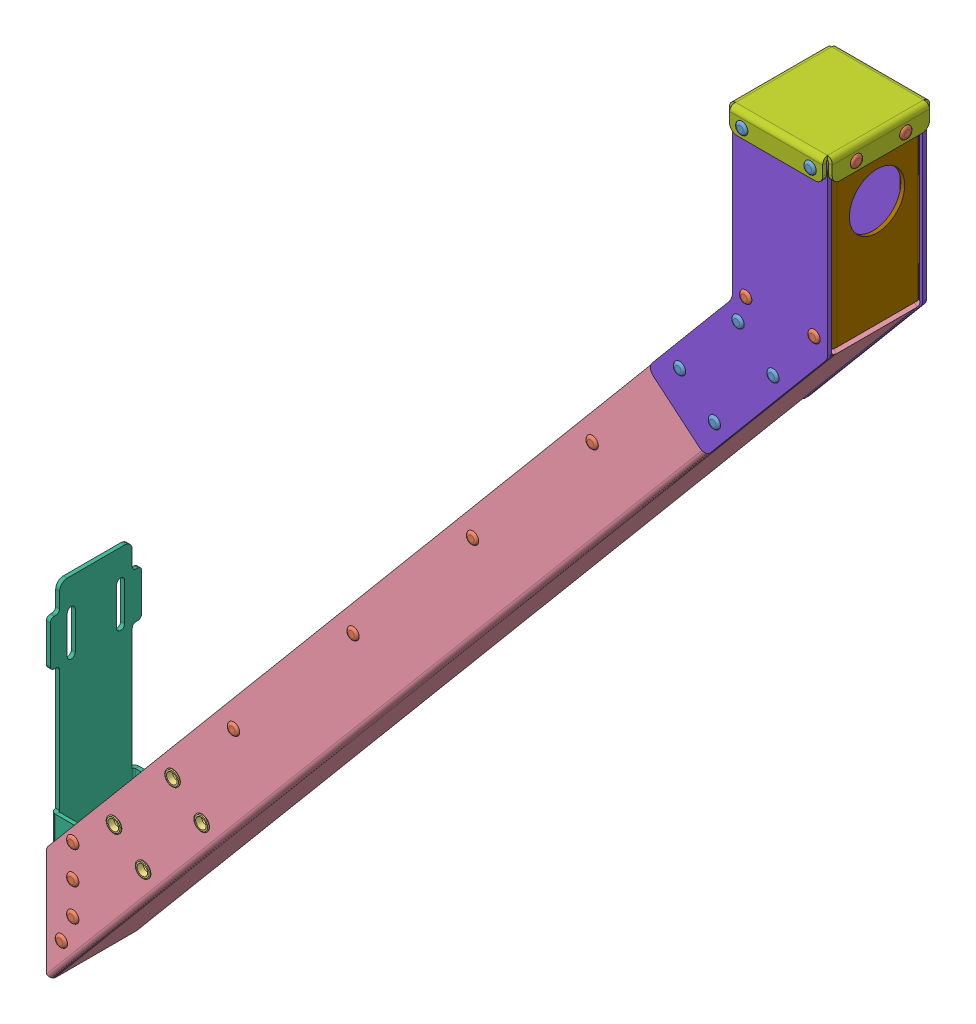
SolidWorks assembly GE-20011, configuration Default. Lengths in mm.
Overall size (724.49 954.81 92.63).
53 component instances, 9 part files, 51 mates.
Components (placement in the parent):
- rivet_.1875_.376-.5-1: rivet_.1875_.376-.5 [Default] at (581.956 765.2734 3.2639) x (-0.945935 -0.324357 0) z (0 0 1) size (10.01 10.01 19.38)
- rivet_.1875_.376-.5-2: rivet_.1875_.376-.5 [Default] at (581.956 765.2734 -79.6417) x (0.53005 0.847966 0) z (0 0 -1) size (10.01 10.01 19.38)
- rivet_.1875_.251-.375-49: rivet_.1875_.251-.375 [Default] at (456.6394 613.4571 0) x (-0.588171 -0.808736 0) z (0 0 1) size (10.01 10.01 16.21)
- rivet_.1875_.251-.375-50: rivet_.1875_.251-.375 [Default] at (456.6394 613.4571 -76.3778) x (0.853096 -0.521754 0) z (0 0 -1) size (10.01 10.01 16.21)
- rivet_.1875_.251-.375-51: rivet_.1875_.251-.375 [Default] at (12.7 30.489 -76.3778) x (0.853096 -0.521754 0) z (0 0 -1) size (10.01 10.01 16.21)
- rivet_.1875_.251-.375-52: rivet_.1875_.251-.375 [Default] at (12.7 30.489 0) x (-0.588171 -0.808736 0) z (0 0 1) size (10.01 10.01 16.21)
- rivnut_.25_20_.165-.260-1: rivnut_.25_20_.165-.260 [Installed] at (105.7322 195.0203 0.762) x (-0.98091 0.19446 0) z (0.19446 0.98091 0) size (12.7 15.11 12.7)
- rivnut_.25_20_.165-.260-9: rivnut_.25_20_.165-.260 [Installed] at (105.7322 195.0203 -77.1398) x (0.831607 0.555365 0) z (-0.555365 0.831607 0) size (12.7 15.11 12.7)
- GE-20011 - 01-1: GE-20011 - 01 [Default] at origin size (656.55 781.22 76.38)
- GE-20011 - 02-1: GE-20011 - 02 [Default] at (576.309 778.3012 -38.1889) x (0 0 -1) z (0.642788 0.766044 0) size (69.85 57.15 838.2)
- rivnut_.25_20_.165-.260-10: rivnut_.25_20_.165-.260 [Installed] at (56.7517 136.6477 -77.1398) x (0.831607 0.555365 0) z (-0.555365 0.831607 0) size (12.7 15.11 12.7)
- rivnut_.25_20_.165-.260-11: rivnut_.25_20_.165-.260 [Installed] at (130.0541 174.6118 -77.1398) x (0.831607 0.555365 0) z (-0.555365 0.831607 0) size (12.7 15.11 12.7)
- rivnut_.25_20_.165-.260-12: rivnut_.25_20_.165-.260 [Installed] at (81.0737 116.2392 -77.1398) x (0.831607 0.555365 0) z (-0.555365 0.831607 0) size (12.7 15.11 12.7)
- rivnut_.25_20_.165-.260-6: rivnut_.25_20_.165-.260 [Installed] at (56.7517 136.6477 0.762) x (-0.98091 0.19446 0) z (0.19446 0.98091 0) size (12.7 15.11 12.7)
- rivnut_.25_20_.165-.260-7: rivnut_.25_20_.165-.260 [Installed] at (130.0541 174.6118 0.762) x (-0.98091 0.19446 0) z (0.19446 0.98091 0) size (12.7 15.11 12.7)
- rivnut_.25_20_.165-.260-8: rivnut_.25_20_.165-.260 [Installed] at (81.0737 116.2392 0.762) x (-0.98091 0.19446 0) z (0.19446 0.98091 0) size (12.7 15.11 12.7)
- GE-20011 - 06-1: GE-20011 - 06 [Default] at (0 1.914 -38.1889) x (0 0 1) z (-1 0 0) size (76.38 279.4 38.1)
- rivet_.1875_.251-.375-53: rivet_.1875_.251-.375 [Default] at (22.225 106.689 -76.3778) x (0.853096 -0.521754 0) z (0 0 -1) size (10.01 10.01 16.21)
- rivet_.1875_.251-.375-54: rivet_.1875_.251-.375 [Default] at (22.225 79.7015 -76.3778) x (0.853096 -0.521754 0) z (0 0 -1) size (10.01 10.01 16.21)
- rivet_.1875_.251-.375-55: rivet_.1875_.251-.375 [Default] at (22.225 52.714 -76.3778) x (0.853096 -0.521754 0) z (0 0 -1) size (10.01 10.01 16.21)
- rivet_.1875_.251-.375-56: rivet_.1875_.251-.375 [Default] at (22.225 106.689 0) x (-0.588171 -0.808736 0) z (0 0 1) size (10.01 10.01 16.21)
- rivet_.1875_.251-.375-57: rivet_.1875_.251-.375 [Default] at (22.225 79.7015 0) x (-0.588171 -0.808736 0) z (0 0 1) size (10.01 10.01 16.21)
- rivet_.1875_.251-.375-58: rivet_.1875_.251-.375 [Default] at (22.225 52.714 0) x (-0.588171 -0.808736 0) z (0 0 1) size (10.01 10.01 16.21)
- rivet_.1875_.251-.375-59: rivet_.1875_.251-.375 [Default] at (356.6377 494.2797 0) x (-0.588171 -0.808736 0) z (0 0 1) size (10.01 10.01 16.21)
- rivet_.1875_.251-.375-60: rivet_.1875_.251-.375 [Default] at (256.636 375.1024 0) x (-0.588171 -0.808736 0) z (0 0 1) size (10.01 10.01 16.21)
- rivet_.1875_.251-.375-61: rivet_.1875_.251-.375 [Default] at (156.6343 255.925 0) x (-0.588171 -0.808736 0) z (0 0 1) size (10.01 10.01 16.21)
- rivet_.1875_.251-.375-63: rivet_.1875_.251-.375 [Default] at (356.6377 494.2797 -76.3778) x (0.853096 -0.521754 0) z (0 0 -1) size (10.01 10.01 16.21)
- rivet_.1875_.251-.375-64: rivet_.1875_.251-.375 [Default] at (256.636 375.1024 -76.3778) x (0.853096 -0.521754 0) z (0 0 -1) size (10.01 10.01 16.21)
- rivet_.1875_.251-.375-65: rivet_.1875_.251-.375 [Default] at (156.6343 255.925 -76.3778) x (0.853096 -0.521754 0) z (0 0 -1) size (10.01 10.01 16.21)
- GE-20011 - 16-1: GE-20011 - 16 [Default] at (577.211 921.6184 -38.1889) x (0 0 1) z (-1 0 0) size (575.88 298.32 621.78)
  - rivet_.1875_.251-.375-1: rivet_.1875_.251-.375 [Default] at (20.6375 -11.4978 3.2639) x (-0.156464 0.987684 0) z (0 0 1) size (10.01 10.01 16.21)
  - rivet_.1875_.251-.375-2: rivet_.1875_.251-.375 [Default] at (20.6375 -11.4978 -82.6389) x (-0.853096 0.521754 0) z (0 0 -1) size (10.01 10.01 16.21)
  - rivet_.1875_.251-.375-3: rivet_.1875_.251-.375 [Default] at (-41.4528 -135.3228 -11.1125) x (0 -0.808736 -0.588171) z (-1 0 0) size (10.01 10.01 16.21)
  - rivet_.1875_.251-.375-4: rivet_.1875_.251-.375 [Default] at (41.4528 -135.3228 -11.1125) x (0 -0.521754 0.853096) z (1 0 0) size (10.01 10.01 16.21)
  - rivet_.1875_.376-.5-1: rivet_.1875_.376-.5 [Default] at (44.7167 -11.4978 -11.1125) x (0 0.15517 -0.987888) z (1 0 0) size (10.01 10.01 19.38)
  - rivet_.1875_.376-.5-2: rivet_.1875_.376-.5 [Default] at (-44.7167 -11.4978 -11.1125) x (0 0.521744 0.853102) z (-1 0 0) size (10.01 10.01 19.38)
  - GE-20011 - 03-1: GE-20011 - 03 [Default] at (0 -3.2639 -39.6875) x (0 0 -1) z (-1 0 0) size (85.9 19.05 89.43)
  - GE-20011 - 05-1: GE-20011 - 05 [Default] at (-38.1889 -126.0268 -55.0531) x (0 -0.766044 0.642788) z (1 0 0) size (264.39 149.03 3.26)
  - GE-20011 - 04-1: GE-20011 - 04 [Default] at (0 -52.4764 0) x (-1 0 0) z (0 0 1) size (76.38 136.53 15.88)
  - GE-20011 - 05-2: GE-20011 - 05 [Default] at (41.4528 -126.0268 -55.0531) x (0 -0.766044 0.642788) z (1 0 0) size (264.39 149.03 3.26)
  - GE-20011 - 04-2: GE-20011 - 04 [Default] at (0 -52.4764 -79.375) x (1 0 0) z (0 0 -1) size (76.38 136.53 15.88)
  - rivet_.1875_.251-.375-5: rivet_.1875_.251-.375 [Default] at (-20.6375 -11.4978 -82.6389) x (-0.853096 0.521754 0) z (0 0 -1) size (10.01 10.01 16.21)
  - rivet_.1875_.251-.375-6: rivet_.1875_.251-.375 [Default] at (-20.6375 -11.4978 3.2639) x (-0.156464 0.987684 0) z (0 0 1) size (10.01 10.01 16.21)
  - rivet_.1875_.376-.5-3: rivet_.1875_.376-.5 [Default] at (-44.7167 -11.4978 -68.2625) x (0 0.521744 0.853102) z (-1 0 0) size (10.01 10.01 19.38)
  - rivet_.1875_.376-.5-4: rivet_.1875_.376-.5 [Default] at (44.7167 -11.4978 -68.2625) x (0 0.15517 -0.987888) z (1 0 0) size (10.01 10.01 19.38)
  - rivet_.1875_.251-.375-7: rivet_.1875_.251-.375 [Default] at (41.4528 -135.3228 -68.2625) x (0 -0.521754 0.853096) z (1 0 0) size (10.01 10.01 16.21)
  - rivet_.1875_.251-.375-8: rivet_.1875_.251-.375 [Default] at (-41.4528 -135.3228 -68.2625) x (0 -0.808736 -0.588171) z (-1 0 0) size (10.01 10.01 16.21)
- rivet_.1875_.376-.5-3: rivet_.1875_.376-.5 [Default] at (532.9756 706.9008 -79.6417) x (0.53005 0.847966 0) z (0 0 -1) size (10.01 10.01 19.38)
- rivet_.1875_.376-.5-4: rivet_.1875_.376-.5 [Default] at (562.1619 682.4106 -79.6417) x (0.53005 0.847966 0) z (0 0 -1) size (10.01 10.01 19.38)
- rivet_.1875_.376-.5-5: rivet_.1875_.376-.5 [Default] at (611.1423 740.7832 -79.6417) x (0.53005 0.847966 0) z (0 0 -1) size (10.01 10.01 19.38)
- rivet_.1875_.376-.5-6: rivet_.1875_.376-.5 [Default] at (532.9756 706.9008 3.2639) x (-0.945935 -0.324357 0) z (0 0 1) size (10.01 10.01 19.38)
- rivet_.1875_.376-.5-7: rivet_.1875_.376-.5 [Default] at (562.1619 682.4106 3.2639) x (-0.945935 -0.324357 0) z (0 0 1) size (10.01 10.01 19.38)
- rivet_.1875_.376-.5-8: rivet_.1875_.376-.5 [Default] at (611.1423 740.7832 3.2639) x (-0.945935 -0.324357 0) z (0 0 1) size (10.01 10.01 19.38)
Mates (geometry in assembly coordinates):
- Coincident1: coincident anti-aligned: plane of GE-20011 - 01-1 through (-52.3991 43.9681 0) normal (-0.766044 0.642788 0); plane of GE-20011 - 02-1 through (8.0292 115.9838 -44.45) normal (0.766044 -0.642788 0)
- Coincident2: coincident anti-aligned: plane of GE-20011 - 01-1 through (0 0 -3.2639) normal (0 0 -1); plane of part 010-1 through (576.8722 874.8333 -3.2639) normal (0 0 1)
- Concentric1: concentric anti-aligned: cylinder of GE-20011 - 01-1 through (565.2356 780.0365 -79.375) axis (-0.766044 0.642788 0) radius 2.4574; cylinder of GE-20011 - 02-1 through (565.2356 780.0365 -79.375) axis (0.766044 -0.642788 0) radius 2.4574
- Concentric2: concentric anti-aligned: cylinder of GE-20011 - 01-1 through (565.2356 780.0365 -9.525) axis (-0.766044 0.642788 0) radius 2.4574; cylinder of GE-20011 - 02-1 through (565.2356 780.0365 -9.525) axis (0.766044 -0.642788 0) radius 2.4574
- Concentric3: concentric aligned: cylinder of GE-20011 - 01-1 through (591.1597 904.9069 0) axis (0 0 1) radius 2.4574; cylinder of part 010-1 through (591.1597 904.9069 -3.2639) axis (0 0 1) radius 2.4574
- Concentric4: concentric anti-aligned: cylinder of GE-20011 - 01-1 through (638.7847 904.9069 0) axis (0 0 1) radius 2.4574; cylinder of part 010-1 through (638.7847 904.9069 -85.6361) axis (0 0 -1) radius 2.4574
- Concentric8: concentric anti-aligned: cylinder of GE-20011 - 02-1 through (565.2356 780.0365 -79.375) axis (0.766044 -0.642788 0) radius 2.4574; cylinder of rivet_.1875_.251-.375-32 through (573.9234 772.7466 -79.375) axis (-0.766044 0.642788 0) radius 2.3813
- Coincident10: coincident aligned: plane of GE-20011 - 02-1 through (5.5289 118.0818 -44.45) normal (-0.766044 0.642788 0); circle of rivet_.1875_.126-.25-2
- Concentric9: concentric anti-aligned: cylinder of GE-20011 - 01-1 through (591.1597 904.9069 0) axis (0 0 1) radius 2.4574; cylinder of rivet_.1875_.251-.375-45 through (591.1597 904.9069 -74.295) axis (0 0 -1) radius 2.3813
- Coincident12: coincident aligned: plane of GE-20011 - 01-1 through (0 0 -76.3778) normal (0 0 -1); circle of rivet_.1875_.126-.25-1
- Concentric11: concentric aligned: cylinder of GE-20011 - 01-1 through (105.7322 195.0203 0) axis (0 0 1) radius 5.08; cylinder of rivnut_.25_20_.165-.260-1 through (105.7322 195.0203 0.762) axis (0 0 1) radius 4.953
- Coincident13: coincident anti-aligned: plane of GE-20011 - 01-1 through (0 0 0) normal (0 0 1); plane of rivnut_.25_20_.165-.260-1 through (111.9609 193.7855 0) normal (0 0 -1)
- Concentric12: concentric anti-aligned: cylinder of GE-20011 - 01-1 through (105.7322 195.0203 0) axis (0 0 1) radius 5.08; cylinder of rivnut_.25_20_.165-.260-9 through (105.7322 195.0203 -77.1398) axis (0 0 -1) radius 4.953
- Coincident14: coincident anti-aligned: plane of GE-20011 - 01-1 through (0 0 -76.3778) normal (0 0 -1); plane of rivnut_.25_20_.165-.260-9 through (100.4515 191.4937 -76.3778) normal (0 0 1)
- Coincident15: coincident aligned: plane of GE-20011 - 01-1 through (0 0 -3.2639) normal (-1 0 0); plane of GE-20011 - 06-1 through (0 1.914 -38.1889) normal (-1 0 0)
- Coincident16: coincident anti-aligned: plane of GE-20011 - 01-1 through (0 0 -3.2639) normal (0 0 -1); plane of GE-20011 - 06-1 through (0 1.914 -3.2639) normal (0 0 1)
- Coincident17: coincident: plane of GE-20011 - 01-1 through (0.9729 -0.8163 0) normal (-0.766044 0.642788 0); line of GE-20011 - 06-1 through (3.2639 1.914 -62.23) axis (0 0 1)
- Concentric13: concentric aligned: cylinder of GE-20011 - 01-1 through (456.6394 613.4571 0) axis (0 0 1) radius 2.4574; cylinder of GE-20011 - 02-1 through (456.6394 613.4571 -3.2639) axis (0 0 1) radius 2.4574
- Coincident19: coincident anti-aligned: plane of GE-20011 - 01-1 through (0 0 -3.2639) normal (0 0 -1); plane of GE-20011 - 02-1 through (576.309 778.3012 -3.2639) normal (0 0 1)
- Concentric14: concentric aligned: cylinder of GE-20011 - 01-1 through (356.6377 494.2797 0) axis (0 0 1) radius 2.4574; cylinder of GE-20011 - 02-1 through (356.6377 494.2797 -3.2639) axis (0 0 1) radius 2.4574
- Concentric15: concentric anti-aligned: cylinder of GE-20011 - 01-1 through (12.7 30.489 0) axis (0 0 1) radius 2.4574; cylinder of rivet_.1875_.251-.375-51 through (12.7 30.489 -61.7728) axis (0 0 -1) radius 2.3813
- Coincident20: coincident anti-aligned: plane of GE-20011 - 01-1 through (0 0 -76.3778) normal (0 0 -1); plane of rivet_.1875_.251-.375-51 through (12.7 30.489 -76.3778) normal (0 0 1)
- Concentric16: concentric aligned: cylinder of GE-20011 - 01-1 through (12.7 30.489 0) axis (0 0 1) radius 2.4574; cylinder of rivet_.1875_.251-.375-52 through (12.7 30.489 -14.605) axis (0 0 1) radius 2.3813
- Coincident21: coincident anti-aligned: plane of GE-20011 - 01-1 through (0 0 0) normal (0 0 1); plane of rivet_.1875_.251-.375-52 through (12.7 30.489 0) normal (0 0 -1)
- Concentric17: concentric aligned: cylinder of GE-20011 - 01-1 through (456.6394 613.4571 0) axis (0 0 1) radius 2.4574; cylinder of rivet_.1875_.251-.375-49 through (456.6394 613.4571 -14.605) axis (0 0 1) radius 2.3813
- Coincident22: coincident aligned: plane of GE-20011 - 01-1 through (0 0 0) normal (0 0 1); circle of rivet_.1875_.251-.375-49
- Concentric18: concentric anti-aligned: cylinder of GE-20011 - 01-1 through (456.6394 613.4571 0) axis (0 0 1) radius 2.4574; cylinder of rivet_.1875_.251-.375-50 through (456.6394 613.4571 -61.7728) axis (0 0 -1) radius 2.3813
- Coincident23: coincident anti-aligned: plane of GE-20011 - 01-1 through (0 0 -76.3778) normal (0 0 -1); plane of rivet_.1875_.251-.375-50 through (456.6394 613.4571 -76.3778) normal (0 0 1)
- Coincident24: coincident anti-aligned: plane of GE-20011 - 01-1 through (0 0 0) normal (0 0 1); plane of GE-20011 - 05-1 through (632.202 795.6437 0) normal (0 0 -1)
- Concentric19: concentric aligned: cylinder of GE-20011 - 01-1 through (532.9756 706.9008 0) axis (0 0 1) radius 2.4574; cylinder of GE-20011 - 05-1 through (532.9136 706.9529 3.2639) axis (0 0 1) radius 2.4574
- Concentric20: concentric aligned: cylinder of GE-20011 - 01-1 through (562.1619 682.4106 0) axis (0 0 1) radius 2.4574; cylinder of GE-20011 - 05-1 through (562.0998 682.4627 3.2639) axis (0 0 1) radius 2.4574
- Concentric21: concentric anti-aligned: cylinder of GE-20011 - 05-1 through (585.1635 786.8323 3.2639) axis (0 0 1) radius 2.4574; cylinder of GE-20011 - 04-1 through (585.1635 786.8323 -76.3778) axis (0 0 -1) radius 2.4574
- Concentric22: concentric anti-aligned: cylinder of GE-20011 - 05-1 through (564.7642 902.5226 3.2639) axis (0 0 1) radius 2.4574; cylinder of GE-20011 - 04-1 through (564.7642 902.5226 -76.3778) axis (0 0 -1) radius 2.4574
- Coincident25: coincident anti-aligned: plane of GE-20011 - 05-1 through (632.202 795.6437 0) normal (0 0 -1); plane of GE-20011 - 04-1 through (560.9363 860.2369 0) normal (0 0 1)
- Coincident26: coincident anti-aligned: plane of GE-20011 - 05-1 through (632.202 795.6437 0) normal (0 0 -1); plane of GE-20011 - 04-2 through (639.1055 874.0202 0) normal (0 0 1)
- Concentric23: concentric aligned: cylinder of GE-20011 - 05-1 through (621.0459 912.4465 3.2639) axis (0 0 1) radius 2.4574; cylinder of GE-20011 - 04-2 through (621.0459 912.4465 0) axis (0 0 1) radius 2.4574
- Concentric24: concentric aligned: cylinder of GE-20011 - 05-1 through (641.4452 796.7563 3.2639) axis (0 0 1) radius 2.4574; cylinder of GE-20011 - 04-2 through (641.4452 796.7563 0) axis (0 0 1) radius 2.4574
- Concentric25: concentric aligned: cylinder of GE-20011 - 05-1 through (621.0459 912.4465 3.2639) axis (0 0 1) radius 2.4574; cylinder of GE-20010 - 16-3 through (607.5142 935.7172 0.8065) axis (0 0 1) radius 2.4574
- Coincident27: coincident anti-aligned: plane of GE-20011 - 01-1 through (0 0 -76.3778) normal (0 0 -1); plane of GE-20011 - 05-2 through (632.202 795.6437 -76.3778) normal (0 0 1)
- Concentric28: concentric aligned: cylinder of GE-20011 - 01-1 through (581.956 765.2734 0) axis (0 0 1) radius 2.4574; cylinder of GE-20011 - 05-2 through (581.894 765.3255 -76.3778) axis (0 0 1) radius 2.4574
- Concentric29: concentric aligned: cylinder of GE-20011 - 01-1 through (611.1423 740.7832 0) axis (0 0 1) radius 2.4574; cylinder of GE-20011 - 05-2 through (611.0803 740.8352 -76.3778) axis (0 0 1) radius 2.4574
- Coincident28: coincident anti-aligned: plane of GE-20011 - 04-1 through (560.9363 860.2369 -38.1889) normal (-0.984808 -0.173648 0); plane of GE-20011 - 03-1 through (552.3907 908.7017 -38.1889) normal (0.984808 0.173648 0)
- Concentric30: concentric anti-aligned: cylinder of GE-20011 - 04-1 through (553.8205 900.5929 -17.5514) axis (-0.984808 -0.173648 0) radius 2.4574; cylinder of GE-20011 - 03-1 through (635.2039 914.943 -17.5514) axis (0.984808 0.173648 0) radius 2.4574
- Coincident29: coincident anti-aligned: cylinder of GE-20011 - 04-1 through (553.8205 900.5929 -58.8264) axis (-0.984808 -0.173648 0) radius 2.4574; circle of GE-20011 - 03-1
- Concentric32: concentric aligned: cylinder of GE-20011 - 01-1 through (581.956 765.2734 0) axis (0 0 1) radius 2.4574; cylinder of GE-20011 - 16-1/GE-20011 - 05-2 through (581.956 765.2734 3.2639) axis (0 0 1) radius 2.4574
- Coincident30: coincident anti-aligned: plane of GE-20011 - 01-1 through (0 0 0) normal (0 0 1); plane of GE-20011 - 16-1/GE-20011 - 05-2 through (632.2641 795.5916 0) normal (0 0 -1)
- Concentric33: concentric aligned: cylinder of GE-20011 - 01-1 through (532.9756 706.9008 0) axis (0 0 1) radius 2.4574; cylinder of GE-20011 - 16-1/GE-20011 - 05-2 through (532.9756 706.9008 3.2639) axis (0 0 1) radius 2.4574
- Concentric34: concentric aligned: cylinder of GE-20011 - 16-1/GE-20011 - 05-2 through (581.956 765.2734 3.2639) axis (0 0 1) radius 2.4574; cylinder of rivet_.1875_.376-.5-1 through (581.956 765.2734 -14.5161) axis (0 0 1) radius 2.3813
- Coincident31: coincident aligned: plane of GE-20011 - 16-1/GE-20011 - 05-2 through (632.2641 795.5916 3.2639) normal (0 0 1); circle of rivet_.1875_.376-.5-1
- Concentric35: concentric anti-aligned: cylinder of GE-20011 - 16-1/GE-20011 - 05-1 through (581.956 765.2734 -76.3778) axis (0 0 1) radius 2.4574; cylinder of rivet_.1875_.376-.5-2 through (581.956 765.2734 -61.8617) axis (0 0 -1) radius 2.3813
- Coincident32: coincident anti-aligned: plane of GE-20011 - 16-1/GE-20011 - 05-1 through (632.2641 795.5916 -79.6417) normal (0 0 -1); plane of rivet_.1875_.376-.5-2 through (581.956 765.2734 -79.6417) normal (0 0 1)
